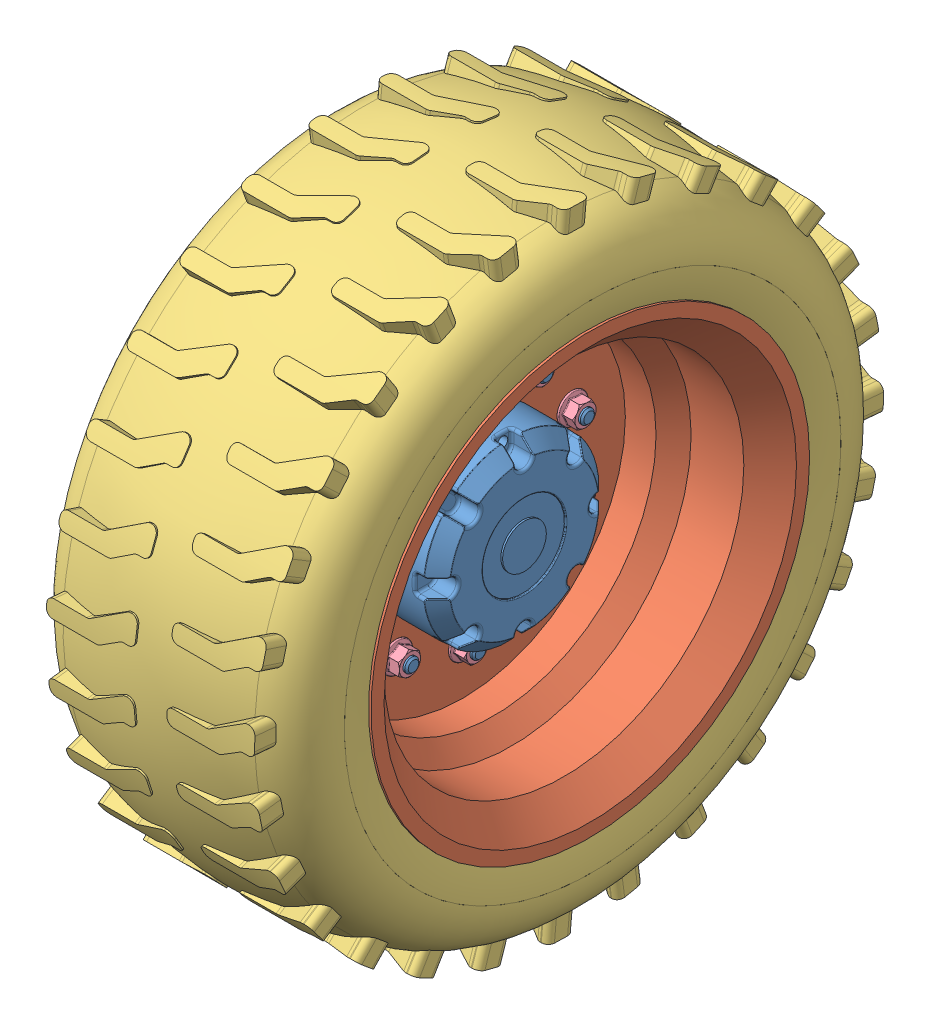
SolidWorks assembly 23.Tire Assembly, configuration Default. Lengths in mm.
Overall size (367.75 904.4 904.4).
13 component instances, 4 part files, 8 mates.
Components (placement in the parent):
- 19.Axle-1: 19.Axle [Default] at (-415.3781 226.5473 319.0258) size (290.35 300 300)
- 20.Rim-1: 20.Rim [Default] at (-200.3781 226.5473 319.0258) size (300 500 500)
- 21.Tire-1: 21.Tire [Default] at (-200.3781 226.5473 319.0258) x (1 0 0) z (0 0.311681 0.950187) size (305.49 716.72 716.72)
- hex flange nut_am-3: hex flange nut_am [B18.2.2.4M - Hex flange nut, M16 x 2 --N] at (-179.3781 266.7195 195.3884) x (0 0.404793 -0.914408) z (1 0 0) size (34.5 34.5 16)
- hex flange nut_am-13: hex flange nut_am [B18.2.2.4M - Hex flange nut, M16 x 2 --N] at (-179.3781 331.7195 242.6137) x (0 0.86496 -0.501841) z (1 0 0) size (34.5 34.5 16)
- hex flange nut_am-14: hex flange nut_am [B18.2.2.4M - Hex flange nut, M16 x 2 --N] at (-179.3781 356.5473 319.0258) x (0 0.994742 0.102413) z (1 0 0) size (34.5 34.5 16)
- hex flange nut_am-15: hex flange nut_am [B18.2.2.4M - Hex flange nut, M16 x 2 --N] at (-179.3781 331.7195 395.4379) x (0 0.744566 0.667549) z (1 0 0) size (34.5 34.5 16)
- hex flange nut_am-16: hex flange nut_am [B18.2.2.4M - Hex flange nut, M16 x 2 --N] at (-179.3781 266.7195 442.6631) x (0 0.209992 0.977703) z (1 0 0) size (34.5 34.5 16)
- hex flange nut_am-17: hex flange nut_am [B18.2.2.4M - Hex flange nut, M16 x 2 --N] at (-179.3781 186.3751 442.6631) x (0 -0.404793 0.914408) z (1 0 0) size (34.5 34.5 16)
- hex flange nut_am-18: hex flange nut_am [B18.2.2.4M - Hex flange nut, M16 x 2 --N] at (-179.3781 121.3751 395.4379) x (0 -0.86496 0.501841) z (1 0 0) size (34.5 34.5 16)
- hex flange nut_am-19: hex flange nut_am [B18.2.2.4M - Hex flange nut, M16 x 2 --N] at (-179.3781 96.5473 319.0258) x (0 -0.994742 -0.102413) z (1 0 0) size (34.5 34.5 16)
- hex flange nut_am-20: hex flange nut_am [B18.2.2.4M - Hex flange nut, M16 x 2 --N] at (-179.3781 121.3751 242.6137) x (0 -0.744566 -0.667549) z (1 0 0) size (34.5 34.5 16)
- hex flange nut_am-21: hex flange nut_am [B18.2.2.4M - Hex flange nut, M16 x 2 --N] at (-179.3781 186.3751 195.3884) x (0 -0.209992 -0.977703) z (1 0 0) size (34.5 34.5 16)
Mates (geometry in assembly coordinates):
- Concentric1: concentric aligned: cylinder of 19.Axle-1 through (-125.3781 226.5473 319.0258) axis (1 0 0) radius 150; cylinder of 20.Rim-1 through (-200.3781 226.5473 319.0258) axis (1 0 0) radius 190
- Concentric2: concentric anti-aligned: cylinder of 19.Axle-1 through (-175.3781 356.5473 319.0258) axis (-1 0 0) radius 8; cylinder of 20.Rim-1 through (-350.3781 356.5473 319.0258) axis (1 0 0) radius 8
- Coincident1: coincident anti-aligned: plane of 19.Axle-1 through (-205.3781 376.5473 319.0258) normal (1 0 0); plane of 20.Rim-1 through (-205.3781 411.5473 319.0258) normal (-1 0 0)
- Concentric3: concentric aligned: cylinder of 20.Rim-1 through (-200.3781 226.5473 319.0258) axis (1 0 0) radius 190; cylinder of 21.Tire-1 through (-200.3781 226.5473 319.0258) axis (1 0 0) radius 240
- Coincident2: coincident aligned: plane of 20.Rim-1 through (-200.3781 226.5473 319.0258) normal (1 0 0); plane of 21.Tire-1 through (-200.3781 226.5473 319.0258) normal (1 0 0)
- Concentric4: concentric anti-aligned: cylinder of 19.Axle-1 through (-175.3781 186.3751 442.6631) axis (-1 0 0) radius 8; cylinder of hex flange nut_am-1 through (-115.3782 186.3751 442.6631) axis (1 0 0) radius 7
- Concentric5: concentric aligned: cylinder of 20.Rim-1 through (-350.3781 266.7195 195.3884) axis (1 0 0) radius 8; cylinder of hex flange nut_am-3 through (-204.4156 266.7195 195.3884) axis (1 0 0) radius 8
- Coincident4: coincident anti-aligned: plane of 20.Rim-1 through (-195.3781 411.5473 319.0258) normal (1 0 0); plane of hex flange nut_am-3 through (-195.3781 257.0044 217.3342) normal (-1 0 0)
